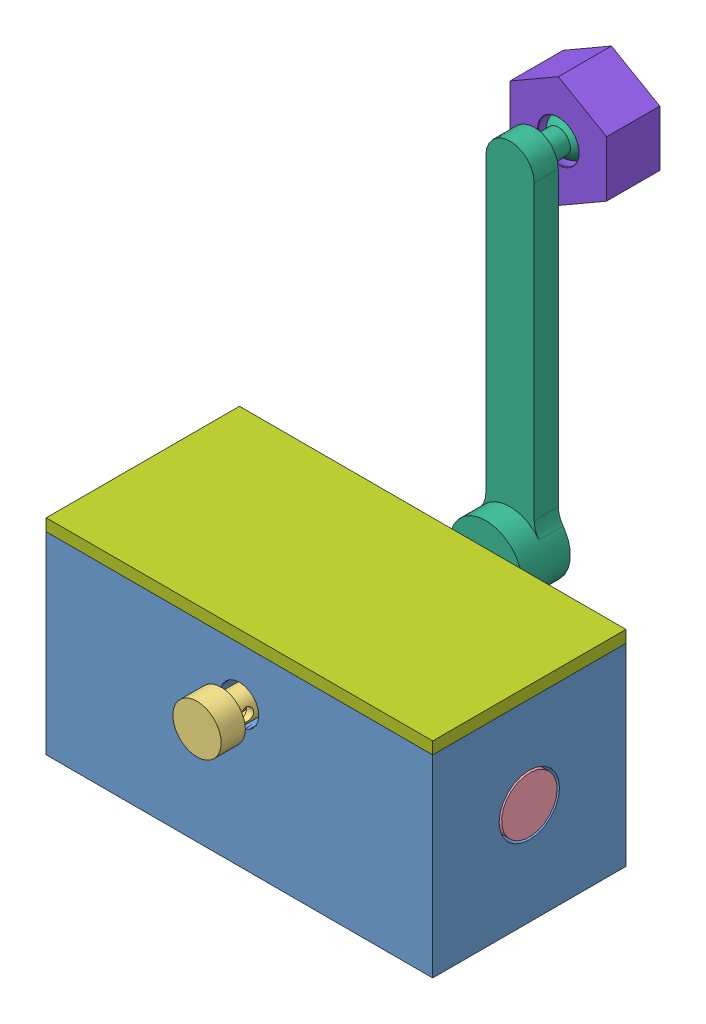
SolidWorks assembly TERM PROJECT ASSEMBLY, configuration Default. Lengths in mm.
Overall size (101.6 137.9 108.96).
8 component instances, 8 part files, 14 mates.
Components (placement in the parent):
- Term Project Base-1: Term Project Base [Default] at (167.2253 65.346 10.5307) size (101.6 50.8 50.8)
- TERM PROJECT KEYWAY-1: TERM PROJECT KEYWAY [Default] at (163.5064 78.1315 -45.2955) x (0.99599 0.089467 0) z (0 0 1) size (3.56 3.56 60.64)
- Term Project gear-1: Term Project gear [Default] at (167.2253 76.8079 15.347) x (-0.99599 -0.089467 0) z (0 0 -1) size (12.7 12.7 44.45)
- Term Project Rod-1: Term Project Rod [Default] at (211.6753 66.616 -14.8693) x (0 0.142218 -0.989835) z (1 0 0) size (14.61 14.61 96.52)
- TERM PROJECT HANDLE CONNECTOR-1: TERM PROJECT HANDLE CONNECTOR [Default] at (167.2253 76.8079 -40.2693) x (0.864547 -0.502551 0) z (0 0 -1) size (12.7 12.7 20.32)
- TERM PROJECT HANDLE-1: TERM PROJECT HANDLE [Default] at (167.2253 76.8079 -66.9393) size (19.05 102.25 29.21)
- TERM PROJECT LID-1: TERM PROJECT LID [Default] at (167.2253 93.921 -14.8693) x (1 0 0) z (0 -1 0) size (101.6 50.8 3.17)
- TERM PROJECT FREE SPINNER-2: TERM PROJECT FREE SPINNER [Default] at (167.2253 163.1799 -73.2893) x (-1 0 0) z (0 0 -1) size (25.4 29.33 13.97)
Mates (geometry in assembly coordinates):
- Concentric1: concentric aligned: circle of Term Project Base-1; circle of Term Project Rod-1
- Coincident2: coincident aligned: plane of Term Project Base-1 through (218.0253 90.746 -40.2693) normal (1 0 0); plane of Term Project Rod-1 through (218.0253 66.616 -14.8693) normal (1 0 0)
- Concentric2: concentric aligned: circle of Term Project Base-1; circle of Term Project gear-1
- Coincident4: coincident anti-aligned: plane of TERM PROJECT KEYWAY-1 through (163.5064 78.1315 15.347) normal (0 0 1); plane of Term Project gear-1 through (167.2253 76.8079 15.347) normal (0 0 -1)
- Coincident5: coincident anti-aligned: line of TERM PROJECT KEYWAY-1 through (163.8245 74.5897 15.347) axis (0.99599 0.089467 0); line of Term Project gear-1 through (169.2931 75.0809 15.347) axis (-0.99599 -0.089467 0)
- Concentric10: concentric aligned: circle of Term Project Base-1; circle of TERM PROJECT HANDLE CONNECTOR-1
- Concentric11: concentric aligned: circle of TERM PROJECT HANDLE-1; circle of TERM PROJECT FREE SPINNER-2
- Coincident14: coincident anti-aligned: circle of TERM PROJECT HANDLE-1; plane of TERM PROJECT FREE SPINNER-2 through (167.2253 163.1799 -215.9719) normal (0 0 1)
- Concentric12: concentric anti-aligned: circle of TERM PROJECT HANDLE CONNECTOR-1; circle of TERM PROJECT HANDLE-1
- Coincident15: coincident anti-aligned: plane of Term Project Base-1 through (167.2253 65.346 -40.2693) normal (0 0 -1); plane of TERM PROJECT HANDLE CONNECTOR-1 through (167.2253 76.8079 -40.2693) normal (0 0 1)
- Coincident16: coincident anti-aligned: plane of TERM PROJECT HANDLE CONNECTOR-1 through (167.2253 76.8079 -60.5893) normal (0 0 -1); plane of TERM PROJECT HANDLE-1 through (167.2253 76.8079 -203.2719) normal (0 0 1)
- Coincident17: coincident: plane of Term Project Base-1 through (116.4253 90.746 -40.2693) normal (0 1 0); plane of TERM PROJECT LID-1 through (96.0771 90.746 -14.8693) normal (0 -1 0)
- Coincident18: coincident: plane of Term Project Base-1 through (167.2253 65.346 10.5307) normal (0 0 1); plane of TERM PROJECT LID-1 through (45.2771 90.746 10.5307) normal (0 0 1)
- Coincident19: coincident aligned: plane of Term Project Base-1 through (218.0253 90.746 -40.2693) normal (1 0 0); plane of TERM PROJECT LID-1 through (146.8771 90.746 10.5307) normal (1 0 0)
